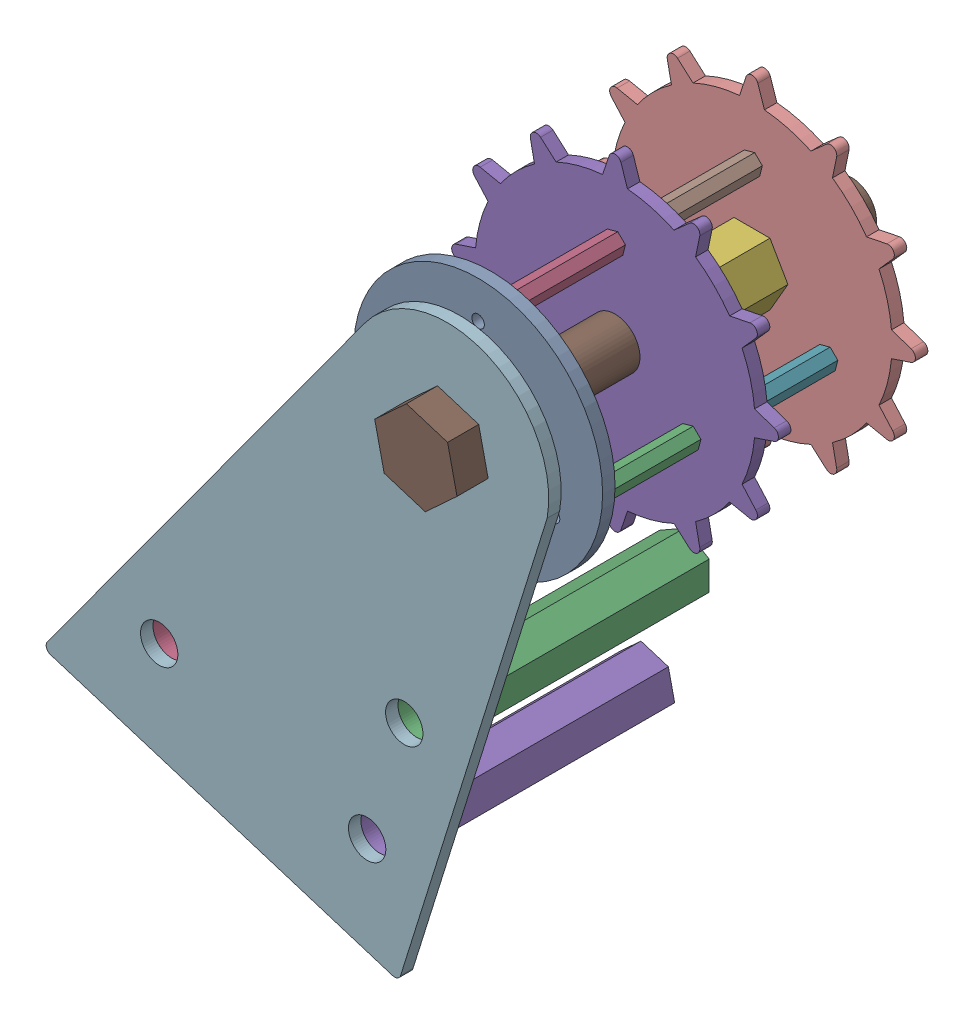
SolidWorks assembly 镜向镜向传动轮, configuration 默认. Lengths in mm.
Overall size (90.9 107.76 70).
17 component instances, 8 part files, 26 mates.
Components (placement in the parent):
- 镜向镜向外侧圆板-1: 镜向镜向外侧圆板 [默认] at (-112.3007 -16.3228 -1) size (40 40 2)
- 镜向镜向齿铜柱-1: 镜向镜向齿铜柱 [默认] at (-124.425 -23.3228 -21) size (3.34 3.35 20)
- 镜向镜向齿铜柱-2: 镜向镜向齿铜柱 [默认] at (-100.1763 -23.3228 -21) x (-0.5 0.866025 0) z (0 0 1) size (3.34 3.35 20)
- 镜向镜向齿铜柱-3: 镜向镜向齿铜柱 [默认] at (-112.3007 -2.3228 -21) x (-0.5 -0.866025 0) z (0 0 1) size (3.34 3.35 20)
- 镜向镜向齿-1: 镜向镜向齿 [默认] at (-112.3007 -16.3228 -23) size (52.5 52.5 2)
- 镜向镜向齿内测铜柱-1: 镜向镜向齿内测铜柱 [默认] at (-112.3007 -16.3228 -43) size (11.55 10 20)
- 镜向镜向齿铜柱-4: 镜向镜向齿铜柱 [默认] at (-100.1763 -23.3228 -43) x (-0.5 0.866025 0) z (0 0 1) size (3.34 3.35 20)
- 镜向镜向齿铜柱-5: 镜向镜向齿铜柱 [默认] at (-112.3007 -2.3228 -43) x (-0.5 -0.866025 0) z (0 0 1) size (3.34 3.35 20)
- 镜向镜向齿铜柱-6: 镜向镜向齿铜柱 [默认] at (-124.425 -23.3228 -43) size (3.34 3.35 20)
- 镜向镜向齿-2: 镜向镜向齿 [默认] at (-112.3007 -16.3228 -45) size (52.5 52.5 2)
- 镜向镜向传动轮螺栓-1: 镜向镜向传动轮螺栓 [默认] at (-112.3007 -16.3228 -59) x (-0.980386 -0.197089 0) z (0 0 1) size (12.15 13.85 70)
- 镜向镜向最外侧支撑板-1: 镜向镜向最外侧支撑板 [默认] at (-120.0559 -95.5444 4) x (0.954528 -0.29812 0) z (0 0 1) size (59.6 94.28 2)
- 镜向镜向8M螺母-1: 镜向镜向8M螺母 [默认] at (-112.3007 -16.3228 1) x (0.96573 0.25955 0) z (0 0 1) size (10.23 11.54 3)
- 镜向镜向8M螺母-2: 镜向镜向8M螺母 [默认] at (-112.3007 -16.3228 -48) size (10.23 11.54 3)
- 镜向镜向43铜柱-1: 镜向镜向43铜柱 [默认] at (-119.167 -59.1547 -39) x (0.999179 -0.040516 0) z (0 0 1) size (8.18 9.23 43)
- 镜向镜向43铜柱-2: 镜向镜向43铜柱 [默认] at (-158.5379 -67.8111 -39) x (-0.336549 -0.941666 0) z (0 0 1) size (8.18 9.23 43)
- 镜向镜向43铜柱-3: 镜向镜向43铜柱 [默认] at (-125.1294 -78.2453 -39) x (-0.336549 -0.941666 0) z (0 0 1) size (8.18 9.23 43)
Mates (geometry in assembly coordinates):
- 同心1: concentric: cylinder of assembly; cylinder of assembly; cylinder of 镜向镜向外侧圆板-1 through (-124.425 -23.3228 -1) axis (0 0 1) radius 1; cylinder of 镜向镜向齿铜柱-1 through (-124.425 -23.3228 -21) axis (0 0 1) radius 1
- 重合1: coincident: plane of assembly; plane of assembly; plane of 镜向镜向外侧圆板-1 through (-112.3007 -16.3228 -1) normal (0 0 -1); plane of 镜向镜向齿铜柱-1 through (-124.425 -23.3228 -1) normal (0 0 1)
- 同心2: concentric: cylinder of assembly; cylinder of assembly; cylinder of 镜向镜向齿铜柱-3 through (-112.3007 -2.3228 -21) axis (0 0 1) radius 1; cylinder of 镜向镜向齿-1 through (-112.3007 -2.3228 -23) axis (0 0 1) radius 1
- 重合2: coincident: plane of assembly; plane of assembly; plane of 镜向镜向齿铜柱-3 through (-112.3007 -2.3228 -21) normal (0 0 -1); plane of 镜向镜向齿-1 through (-112.3007 -16.3228 -21) normal (0 0 1)
- 同心3: concentric: cylinder of assembly; cylinder of assembly; cylinder of 镜向镜向齿铜柱-2 through (-100.1763 -23.3228 -21) axis (0 0 1) radius 1; cylinder of 镜向镜向齿-1 through (-100.1763 -23.3228 -23) axis (0 0 1) radius 1
- 同心4: concentric: cylinder of assembly; cylinder of assembly; cylinder of 镜向镜向外侧圆板-1 through (-100.1763 -23.3228 -1) axis (0 0 1) radius 1; cylinder of 镜向镜向齿铜柱-2 through (-100.1763 -23.3228 -21) axis (0 0 1) radius 1
- 同心5: concentric: cylinder of assembly; cylinder of assembly; cylinder of 镜向镜向齿-1 through (-112.3007 -16.3228 -23) axis (0 0 1) radius 4; cylinder of 镜向镜向齿内测铜柱-1 through (-112.3007 -16.3228 -43) axis (0 0 1) radius 4
- 重合3: coincident: plane of assembly; plane of assembly; plane of 镜向镜向齿-1 through (-112.3007 -16.3228 -23) normal (0 0 -1); plane of 镜向镜向齿内测铜柱-1 through (-112.3007 -16.3228 -23) normal (0 0 1)
- 同心6: concentric: cylinder of assembly; cylinder of assembly; cylinder of 镜向镜向齿-1 through (-100.1763 -23.3228 -23) axis (0 0 1) radius 1; cylinder of 镜向镜向齿铜柱-4 through (-100.1763 -23.3228 -43) axis (0 0 1) radius 1
- 重合4: coincident: plane of assembly; plane of assembly; plane of 镜向镜向齿-1 through (-112.3007 -16.3228 -23) normal (0 0 -1); plane of 镜向镜向齿铜柱-4 through (-100.1763 -23.3228 -23) normal (0 0 1)
- 同心7: concentric: cylinder of assembly; cylinder of assembly; cylinder of 镜向镜向齿铜柱-4 through (-100.1763 -23.3228 -43) axis (0 0 1) radius 1; cylinder of 镜向镜向齿-2 through (-100.1763 -23.3228 -45) axis (0 0 1) radius 1
- 同心8: concentric: cylinder of assembly; cylinder of assembly; cylinder of 镜向镜向齿铜柱-5 through (-112.3007 -2.3228 -43) axis (0 0 1) radius 1; cylinder of 镜向镜向齿-2 through (-112.3007 -2.3228 -45) axis (0 0 1) radius 1
- 重合5: coincident: plane of assembly; plane of assembly; plane of 镜向镜向齿铜柱-5 through (-112.3007 -2.3228 -43) normal (0 0 -1); plane of 镜向镜向齿-2 through (-112.3007 -16.3228 -43) normal (0 0 1)
- 同心9: concentric: cylinder of assembly; cylinder of assembly; cylinder of 镜向镜向齿内测铜柱-1 through (-112.3007 -16.3228 -43) axis (0 0 1) radius 4; cylinder of 镜向镜向传动轮螺栓-1 through (-112.3007 -16.3228 6) axis (0 0 -1) radius 4
- 重合6: coincident: plane of assembly; plane of assembly; plane of 镜向镜向传动轮螺栓-1 through (-112.3007 -16.3228 6) normal (0 0 -1); plane of 镜向镜向最外侧支撑板-1 through (-120.0559 -95.5444 6) normal (0 0 1)
- 同心10: concentric: cylinder of assembly; cylinder of assembly; cylinder of 镜向镜向传动轮螺栓-1 through (-112.3007 -16.3228 6) axis (0 0 -1) radius 4; cylinder of 镜向镜向8M螺母-1 through (-112.3007 -16.3228 1) axis (0 0 1) radius 4
- 重合7: coincident: plane of assembly; plane of assembly; plane of 镜向镜向最外侧支撑板-1 through (-120.0559 -95.5444 4) normal (0 0 -1); plane of 镜向镜向8M螺母-1 through (-112.3007 -16.3228 4) normal (0 0 1)
- 重合8: coincident: plane of assembly; plane of assembly; plane of 镜向镜向外侧圆板-1 through (-112.3007 -16.3228 1) normal (0 0 1); plane of 镜向镜向8M螺母-1 through (-112.3007 -16.3228 1) normal (0 0 -1)
- 同心11: concentric: cylinder of assembly; cylinder of assembly; cylinder of 镜向镜向传动轮螺栓-1 through (-112.3007 -16.3228 6) axis (0 0 -1) radius 4; cylinder of 镜向镜向8M螺母-2 through (-112.3007 -16.3228 -48) axis (0 0 1) radius 4
- 重合9: coincident: plane of assembly; plane of assembly; plane of 镜向镜向齿-2 through (-112.3007 -16.3228 -45) normal (0 0 -1); plane of 镜向镜向8M螺母-2 through (-112.3007 -16.3228 -45) normal (0 0 1)
- 同心12: concentric: cylinder of assembly; cylinder of assembly; cylinder of 镜向镜向最外侧支撑板-1 through (-119.167 -59.1547 4) axis (0 0 1) radius 3; cylinder of 镜向镜向43铜柱-1 through (-119.167 -59.1547 -39.001) axis (0 0 1) radius 3
- 重合10: coincident: plane of assembly; plane of assembly; plane of 镜向镜向最外侧支撑板-1 through (-120.0559 -95.5444 4) normal (0 0 -1); plane of 镜向镜向43铜柱-1 through (-119.167 -59.1547 4) normal (0 0 1)
- 同心13: concentric: cylinder of assembly; cylinder of assembly; cylinder of 镜向镜向最外侧支撑板-1 through (-125.1294 -78.2453 4) axis (0 0 1) radius 3; cylinder of 镜向镜向43铜柱-3 through (-125.1294 -78.2453 -39.001) axis (0 0 1) radius 3
- 重合11: coincident: plane of assembly; plane of assembly; plane of 镜向镜向最外侧支撑板-1 through (-120.0559 -95.5444 4) normal (0 0 -1); plane of 镜向镜向43铜柱-3 through (-125.1294 -78.2453 4) normal (0 0 1)
- 同心14: concentric: cylinder of assembly; cylinder of assembly; cylinder of 镜向镜向最外侧支撑板-1 through (-158.5379 -67.8111 4) axis (0 0 1) radius 3; cylinder of 镜向镜向43铜柱-2 through (-158.5379 -67.8111 -39.001) axis (0 0 1) radius 3
- 重合12: coincident: plane of assembly; plane of assembly; plane of 镜向镜向最外侧支撑板-1 through (-120.0559 -95.5444 4) normal (0 0 -1); plane of 镜向镜向43铜柱-2 through (-158.5379 -67.8111 4) normal (0 0 1)
